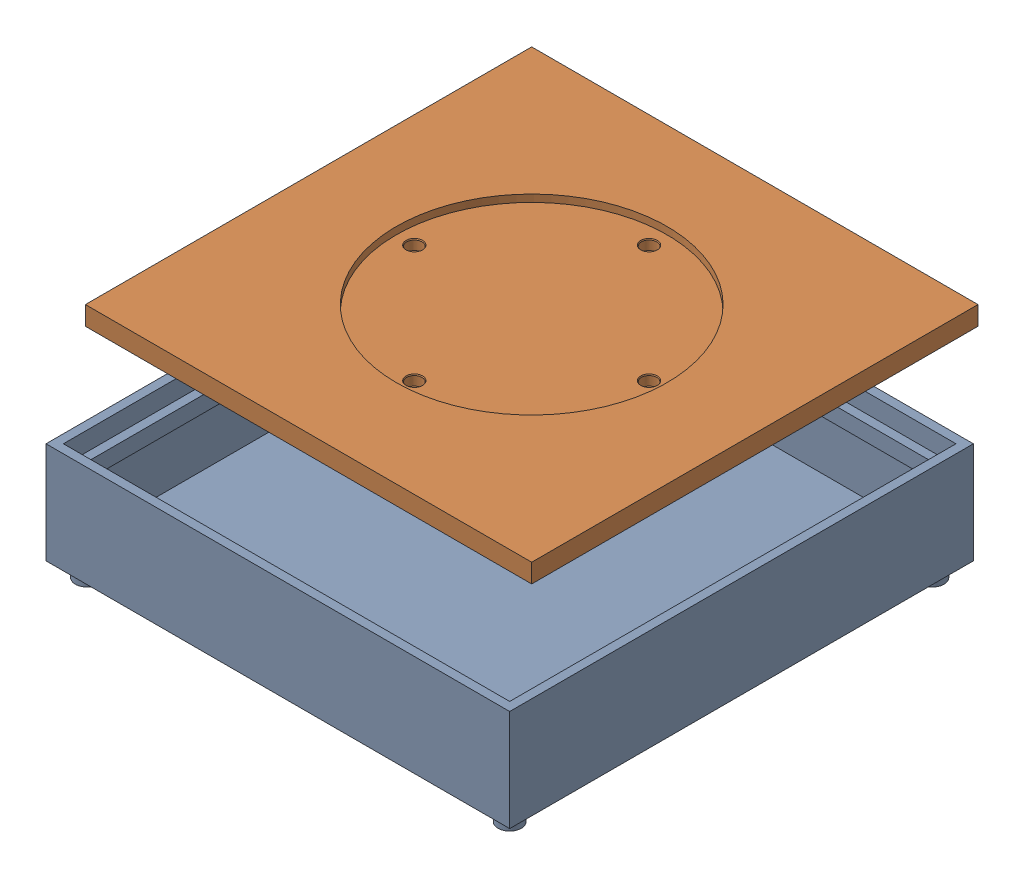
SolidWorks assembly box+lid_for_Image, configuration Default. Lengths in mm.
Overall size (160 76.86 165.54).
2 component instances, 2 part files, 0 mates.
Components (placement in the parent):
- box-1: box [Default] at origin size (160 40 160)
- lid-1: lid [Default] at (-0.9494 65.3587 -8.54) size (154 6.5 154)
